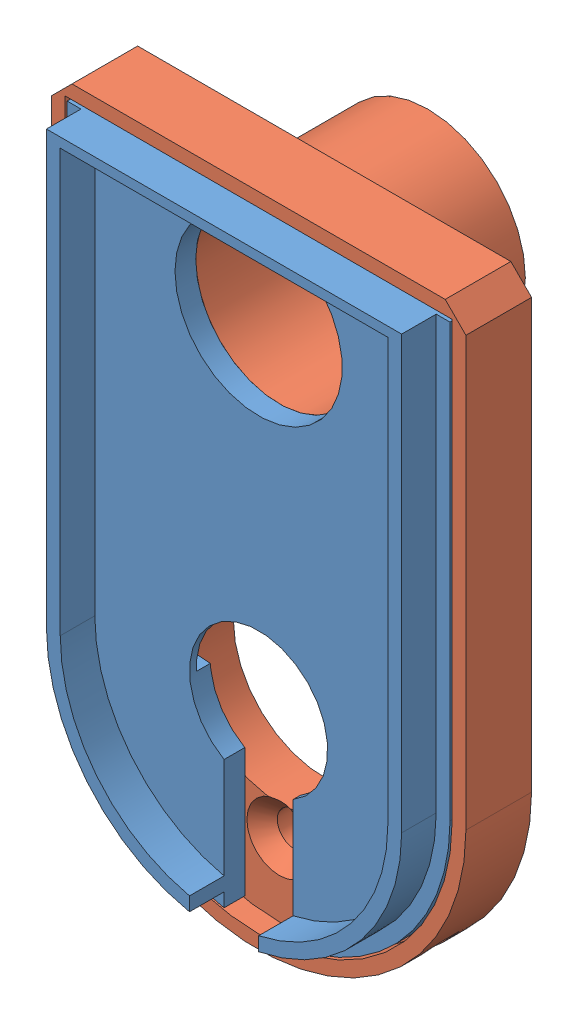
SolidWorks assembly montagem_dust_shoe, configuration Default. Lengths in mm.
Overall size (60 95 29.5).
2 component instances, 2 part files, 3 mates.
Components (placement in the parent):
- parte_inferior-1: parte_inferior [Default] at (28.3135 98.547 51.8438) x (-1 0 0) z (0 0 -1) size (55.4 89.74 8)
- parte_superior-1: parte_superior [Default] at (28.3135 98.547 42.3438) size (60 95 24.5)
Mates (geometry in assembly coordinates):
- Coincident2: coincident anti-aligned: plane of parte_inferior-1 through (28.3135 98.547 48.8438) normal (0 0 -1); plane of parte_superior-1 through (28.3135 98.547 48.8438) normal (0 0 1)
- Concentric5: concentric anti-aligned: circle of parte_inferior-1; circle of parte_superior-1
- Parallel2: parallel aligned: plane of parte_inferior-1 through (56.0135 161.047 51.8438) normal (0 1 0); plane of parte_superior-1 through (-1.6865 163.547 137.3028) normal (0 1 0)
